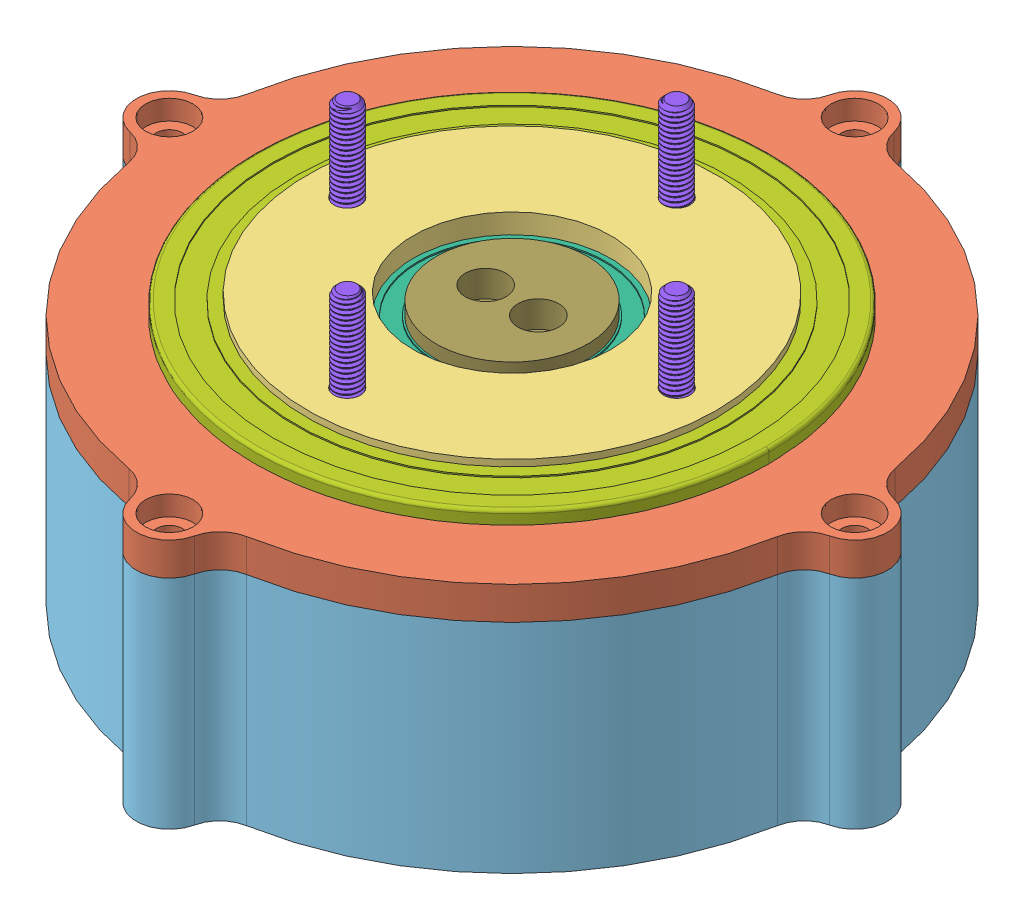
SolidWorks assembly Cycloidal Drive v1.2, configuration Default. Lengths in mm.
Overall size (114 54 114).
165 component instances, 18 part files, 39 mates.
Components (placement in the parent):
- Cycloid v1.4-2: Cycloid v1.4 [Default] at (0.2483 21.0104 2.4876) x (0.928028 0 -0.37251) z (0.37251 0 0.928028) size (80.42 7.02 80.39)
- Cycloid v1.4-1: Cycloid v1.4 [Default] at (-0.2483 13.0076 -2.4876) x (0.977963 0 0.208778) z (-0.208778 0 0.977963) size (80.42 7.02 80.39)
- Top v1.0-2: Top v1.0 [Default] at (0 33 0) x (1 0 0) z (0 1 0) size (114 114 9)
- TopCap v1.1-2: TopCap v1.1 [Default] at (0 38 0) x (1 0 0.000064) z (0 1 0) size (61.99 61.99 13)
- BottomCap v1.1-2: BottomCap v1.1 [Default] at (0 1 0) x (1 0 0) z (0 -1 0) size (63.99 63.99 12)
- Housing v1.3-1: Housing v1.3 [Default] at origin size (114 33 114)
- 6804-3: 6804 [Default] at (0 34.4948 0) x (0 1 0) z (0 0 -1) size (7.01 32.02 32)
- 6804-2: 6804 [Default] at (0.2483 24.5052 2.4876) x (0 1 0) z (0 0 -1) size (7.01 32.02 32)
- 6804-1: 6804 [Default] at (-0.2483 16.5024 -2.4876) x (0 1 0) z (1 0 0) size (7.01 32.02 32)
- 6812-1: 6812 [Default] at (0 6.0038 0) x (0 1 0) z (0 0 -1) size (10.01 78 78)
- 6812-2: 6812 [Default] at (0 35.0038 0) x (0 -1 0) z (0 0 1) size (10.01 78 78)
- MR84ZZ-5: MR84ZZ [Default] at (-25 13.0076 -0.0016) x (0 1 0) z (0.000038 0 -1) size (3 9.83 9.83) (hidden)
  - MR84ZZ_3-1: MR84ZZ_3 [Default] at origin size (0.15 7.4 7.4)
  - MR84ZZ_5-1: MR84ZZ_5 [Default] at (1.5 1.5 2.5981) x (1 0 0) z (0 -1 0) size (1.2 1.2 1.2) (hidden)
  - MR84ZZ_5-2: MR84ZZ_5 [Default] at (1.5 2.5981 1.5) x (1 0 0) z (0 -1 0) size (1.2 1.2 1.2) (hidden)
  - MR84ZZ_5-3: MR84ZZ_5 [Default] at (1.5 3 0) x (1 0 0) z (0 -1 0) size (1.2 1.2 1.2) (hidden)
  - MR84ZZ_5-4: MR84ZZ_5 [Default] at (1.5 2.5981 -1.5) x (1 0 0) z (0 -1 0) size (1.2 1.2 1.2) (hidden)
  - MR84ZZ_5-5: MR84ZZ_5 [Default] at (1.5 1.5 -2.5981) x (1 0 0) z (0 -1 0) size (1.2 1.2 1.2) (hidden)
  - MR84ZZ_5-6: MR84ZZ_5 [Default] at (1.5 0 -3) x (1 0 0) z (0 -1 0) size (1.2 1.2 1.2) (hidden)
  - MR84ZZ_5-7: MR84ZZ_5 [Default] at (1.5 -1.5 -2.5981) x (1 0 0) z (0 -1 0) size (1.2 1.2 1.2) (hidden)
  - MR84ZZ_5-8: MR84ZZ_5 [Default] at (1.5 -2.5981 -1.5) x (1 0 0) z (0 -1 0) size (1.2 1.2 1.2) (hidden)
  - MR84ZZ_5-9: MR84ZZ_5 [Default] at (1.5 -3 0) x (1 0 0) z (0 -1 0) size (1.2 1.2 1.2) (hidden)
  - MR84ZZ_5-10: MR84ZZ_5 [Default] at (1.5 -2.5981 1.5) x (1 0 0) z (0 -1 0) size (1.2 1.2 1.2) (hidden)
  - MR84ZZ_5-11: MR84ZZ_5 [Default] at (1.5 -1.5 2.5981) x (1 0 0) z (0 -1 0) size (1.2 1.2 1.2) (hidden)
  - MR84ZZ_5-12: MR84ZZ_5 [Default] at (1.5 0 3) x (1 0 0) z (0 -1 0) size (1.2 1.2 1.2) (hidden)
  - MR84ZZ_18-1: MR84ZZ_18 [Default] at (0.3984 0 0) x (-1 0 0) z (0 -1 0) size (0.15 7.4 7.4)
  - MR84ZZ_20-1: MR84ZZ_20 [Default] x (1 0 0) z (0 -1 0) size (3 5.29 5.29)
  - MR84ZZ_22-1: MR84ZZ_22 [Default] at origin size (3 9.83 9.83)
- MR84ZZ-1: MR84ZZ [Default] at (-25 21.0104 -0.0016) x (0 1 0) z (0.000038 0 -1) size (3 9.83 9.83) (hidden)
  - MR84ZZ_3-1: MR84ZZ_3 [Default] at origin size (0.15 7.4 7.4)
  - MR84ZZ_5-1: MR84ZZ_5 [Default] at (1.5 1.5 2.5981) x (1 0 0) z (0 -1 0) size (1.2 1.2 1.2) (hidden)
  - MR84ZZ_5-2: MR84ZZ_5 [Default] at (1.5 2.5981 1.5) x (1 0 0) z (0 -1 0) size (1.2 1.2 1.2) (hidden)
  - MR84ZZ_5-3: MR84ZZ_5 [Default] at (1.5 3 0) x (1 0 0) z (0 -1 0) size (1.2 1.2 1.2) (hidden)
  - MR84ZZ_5-4: MR84ZZ_5 [Default] at (1.5 2.5981 -1.5) x (1 0 0) z (0 -1 0) size (1.2 1.2 1.2) (hidden)
  - MR84ZZ_5-5: MR84ZZ_5 [Default] at (1.5 1.5 -2.5981) x (1 0 0) z (0 -1 0) size (1.2 1.2 1.2) (hidden)
  - MR84ZZ_5-6: MR84ZZ_5 [Default] at (1.5 0 -3) x (1 0 0) z (0 -1 0) size (1.2 1.2 1.2) (hidden)
  - MR84ZZ_5-7: MR84ZZ_5 [Default] at (1.5 -1.5 -2.5981) x (1 0 0) z (0 -1 0) size (1.2 1.2 1.2) (hidden)
  - MR84ZZ_5-8: MR84ZZ_5 [Default] at (1.5 -2.5981 -1.5) x (1 0 0) z (0 -1 0) size (1.2 1.2 1.2) (hidden)
  - MR84ZZ_5-9: MR84ZZ_5 [Default] at (1.5 -3 0) x (1 0 0) z (0 -1 0) size (1.2 1.2 1.2) (hidden)
  - MR84ZZ_5-10: MR84ZZ_5 [Default] at (1.5 -2.5981 1.5) x (1 0 0) z (0 -1 0) size (1.2 1.2 1.2) (hidden)
  - MR84ZZ_5-11: MR84ZZ_5 [Default] at (1.5 -1.5 2.5981) x (1 0 0) z (0 -1 0) size (1.2 1.2 1.2) (hidden)
  - MR84ZZ_5-12: MR84ZZ_5 [Default] at (1.5 0 3) x (1 0 0) z (0 -1 0) size (1.2 1.2 1.2) (hidden)
  - MR84ZZ_18-1: MR84ZZ_18 [Default] at (0.3984 0 0) x (-1 0 0) z (0 -1 0) size (0.15 7.4 7.4)
  - MR84ZZ_20-1: MR84ZZ_20 [Default] x (1 0 0) z (0 -1 0) size (3 5.29 5.29)
  - MR84ZZ_22-1: MR84ZZ_22 [Default] at origin size (3 9.83 9.83)
- M4_50-1: M4_50 [Default] at (-187.5016 -66 37.45) size (7.2 54 7.2)
- Dowel Pin-1: Dowel Pin [Default] at (-21.5 3 -37.2391) x (0.714611 0 -0.699522) z (0.699522 0 0.714611) size (6 30 6) (hidden)
- Dowel Pin-9: Dowel Pin [Default] at (7.4669 3 -42.3467) x (0.997068 0 -0.076522) z (0.076522 0 0.997068) size (6 30 6) (hidden)
- Dowel Pin-8: Dowel Pin [Default] at (32.9399 3 -27.6399) x (0.812986 0 0.582283) z (-0.582283 0 0.812986) size (6 30 6) (hidden)
- Dowel Pin-7: Dowel Pin [Default] at (43 3 0) x (0.248499 0 0.968632) z (-0.968632 0 0.248499) size (6 30 6) (hidden)
- Dowel Pin-6: Dowel Pin [Default] at (32.9399 3 27.6399) x (-0.432264 0 0.901747) z (-0.901747 0 -0.432264) size (6 30 6) (hidden)
- Dowel Pin-5: Dowel Pin [Default] at (7.4669 3 42.3467) x (-0.910765 0 0.412925) z (-0.412925 0 -0.910765) size (6 30 6) (hidden)
- Dowel Pin-4: Dowel Pin [Default] at (-21.5 3 37.2391) x (-0.963109 0 -0.26911) z (0.26911 0 -0.963109) size (6 30 6) (hidden)
- Dowel Pin-3: Dowel Pin [Default] at (-40.4068 3 14.7069) x (-0.564804 0 -0.825225) z (0.825225 0 -0.564804) size (6 30 6) (hidden)
- Dowel Pin-2: Dowel Pin [Default] at (-40.4068 3 -14.7069) x (0.097779 0 -0.995208) z (0.995208 0 0.097779) size (6 30 6) (hidden)
- M4_50-2: M4_50 [Default] at (-37.45 -66 -187.5016) x (0 0 1) z (-1 0 0) size (7.2 54 7.2)
- M4_50-3: M4_50 [Default] at (187.5016 -66 -37.45) x (-1 0 0) z (0 0 -1) size (7.2 54 7.2)
- M4_50-4: M4_50 [Default] at (37.45 -66 187.5016) x (0 0 -1) z (1 0 0) size (7.2 54 7.2)
- MR84ZZ-2: MR84ZZ [Default] at (0.0016 21.0104 -25) x (0 1 0) z (1 0 0.000038) size (3 9.83 9.83) (hidden)
  - MR84ZZ_3-1: MR84ZZ_3 [Default] at origin size (0.15 7.4 7.4)
  - MR84ZZ_5-1: MR84ZZ_5 [Default] at (1.5 1.5 2.5981) x (1 0 0) z (0 -1 0) size (1.2 1.2 1.2) (hidden)
  - MR84ZZ_5-2: MR84ZZ_5 [Default] at (1.5 2.5981 1.5) x (1 0 0) z (0 -1 0) size (1.2 1.2 1.2) (hidden)
  - MR84ZZ_5-3: MR84ZZ_5 [Default] at (1.5 3 0) x (1 0 0) z (0 -1 0) size (1.2 1.2 1.2) (hidden)
  - MR84ZZ_5-4: MR84ZZ_5 [Default] at (1.5 2.5981 -1.5) x (1 0 0) z (0 -1 0) size (1.2 1.2 1.2) (hidden)
  - MR84ZZ_5-5: MR84ZZ_5 [Default] at (1.5 1.5 -2.5981) x (1 0 0) z (0 -1 0) size (1.2 1.2 1.2) (hidden)
  - MR84ZZ_5-6: MR84ZZ_5 [Default] at (1.5 0 -3) x (1 0 0) z (0 -1 0) size (1.2 1.2 1.2) (hidden)
  - MR84ZZ_5-7: MR84ZZ_5 [Default] at (1.5 -1.5 -2.5981) x (1 0 0) z (0 -1 0) size (1.2 1.2 1.2) (hidden)
  - MR84ZZ_5-8: MR84ZZ_5 [Default] at (1.5 -2.5981 -1.5) x (1 0 0) z (0 -1 0) size (1.2 1.2 1.2) (hidden)
  - MR84ZZ_5-9: MR84ZZ_5 [Default] at (1.5 -3 0) x (1 0 0) z (0 -1 0) size (1.2 1.2 1.2) (hidden)
  - MR84ZZ_5-10: MR84ZZ_5 [Default] at (1.5 -2.5981 1.5) x (1 0 0) z (0 -1 0) size (1.2 1.2 1.2) (hidden)
  - MR84ZZ_5-11: MR84ZZ_5 [Default] at (1.5 -1.5 2.5981) x (1 0 0) z (0 -1 0) size (1.2 1.2 1.2) (hidden)
  - MR84ZZ_5-12: MR84ZZ_5 [Default] at (1.5 0 3) x (1 0 0) z (0 -1 0) size (1.2 1.2 1.2) (hidden)
  - MR84ZZ_18-1: MR84ZZ_18 [Default] at (0.3984 0 0) x (-1 0 0) z (0 -1 0) size (0.15 7.4 7.4)
  - MR84ZZ_20-1: MR84ZZ_20 [Default] x (1 0 0) z (0 -1 0) size (3 5.29 5.29)
  - MR84ZZ_22-1: MR84ZZ_22 [Default] at origin size (3 9.83 9.83)
- MR84ZZ-3: MR84ZZ [Default] at (25 21.0104 0.0016) x (0 1 0) z (-0.000038 0 1) size (3 9.83 9.83) (hidden)
  - MR84ZZ_3-1: MR84ZZ_3 [Default] at origin size (0.15 7.4 7.4)
  - MR84ZZ_5-1: MR84ZZ_5 [Default] at (1.5 1.5 2.5981) x (1 0 0) z (0 -1 0) size (1.2 1.2 1.2) (hidden)
  - MR84ZZ_5-2: MR84ZZ_5 [Default] at (1.5 2.5981 1.5) x (1 0 0) z (0 -1 0) size (1.2 1.2 1.2) (hidden)
  - MR84ZZ_5-3: MR84ZZ_5 [Default] at (1.5 3 0) x (1 0 0) z (0 -1 0) size (1.2 1.2 1.2) (hidden)
  - MR84ZZ_5-4: MR84ZZ_5 [Default] at (1.5 2.5981 -1.5) x (1 0 0) z (0 -1 0) size (1.2 1.2 1.2) (hidden)
  - MR84ZZ_5-5: MR84ZZ_5 [Default] at (1.5 1.5 -2.5981) x (1 0 0) z (0 -1 0) size (1.2 1.2 1.2) (hidden)
  - MR84ZZ_5-6: MR84ZZ_5 [Default] at (1.5 0 -3) x (1 0 0) z (0 -1 0) size (1.2 1.2 1.2) (hidden)
  - MR84ZZ_5-7: MR84ZZ_5 [Default] at (1.5 -1.5 -2.5981) x (1 0 0) z (0 -1 0) size (1.2 1.2 1.2) (hidden)
  - MR84ZZ_5-8: MR84ZZ_5 [Default] at (1.5 -2.5981 -1.5) x (1 0 0) z (0 -1 0) size (1.2 1.2 1.2) (hidden)
  - MR84ZZ_5-9: MR84ZZ_5 [Default] at (1.5 -3 0) x (1 0 0) z (0 -1 0) size (1.2 1.2 1.2) (hidden)
  - MR84ZZ_5-10: MR84ZZ_5 [Default] at (1.5 -2.5981 1.5) x (1 0 0) z (0 -1 0) size (1.2 1.2 1.2) (hidden)
  - MR84ZZ_5-11: MR84ZZ_5 [Default] at (1.5 -1.5 2.5981) x (1 0 0) z (0 -1 0) size (1.2 1.2 1.2) (hidden)
  - MR84ZZ_5-12: MR84ZZ_5 [Default] at (1.5 0 3) x (1 0 0) z (0 -1 0) size (1.2 1.2 1.2) (hidden)
  - MR84ZZ_18-1: MR84ZZ_18 [Default] at (0.3984 0 0) x (-1 0 0) z (0 -1 0) size (0.15 7.4 7.4)
  - MR84ZZ_20-1: MR84ZZ_20 [Default] x (1 0 0) z (0 -1 0) size (3 5.29 5.29)
  - MR84ZZ_22-1: MR84ZZ_22 [Default] at origin size (3 9.83 9.83)
- MR84ZZ-4: MR84ZZ [Default] at (-0.0016 21.0104 25) x (0 1 0) z (-1 0 -0.000038) size (3 9.83 9.83) (hidden)
  - MR84ZZ_3-1: MR84ZZ_3 [Default] at origin size (0.15 7.4 7.4)
  - MR84ZZ_5-1: MR84ZZ_5 [Default] at (1.5 1.5 2.5981) x (1 0 0) z (0 -1 0) size (1.2 1.2 1.2) (hidden)
  - MR84ZZ_5-2: MR84ZZ_5 [Default] at (1.5 2.5981 1.5) x (1 0 0) z (0 -1 0) size (1.2 1.2 1.2) (hidden)
  - MR84ZZ_5-3: MR84ZZ_5 [Default] at (1.5 3 0) x (1 0 0) z (0 -1 0) size (1.2 1.2 1.2) (hidden)
  - MR84ZZ_5-4: MR84ZZ_5 [Default] at (1.5 2.5981 -1.5) x (1 0 0) z (0 -1 0) size (1.2 1.2 1.2) (hidden)
  - MR84ZZ_5-5: MR84ZZ_5 [Default] at (1.5 1.5 -2.5981) x (1 0 0) z (0 -1 0) size (1.2 1.2 1.2) (hidden)
  - MR84ZZ_5-6: MR84ZZ_5 [Default] at (1.5 0 -3) x (1 0 0) z (0 -1 0) size (1.2 1.2 1.2) (hidden)
  - MR84ZZ_5-7: MR84ZZ_5 [Default] at (1.5 -1.5 -2.5981) x (1 0 0) z (0 -1 0) size (1.2 1.2 1.2) (hidden)
  - MR84ZZ_5-8: MR84ZZ_5 [Default] at (1.5 -2.5981 -1.5) x (1 0 0) z (0 -1 0) size (1.2 1.2 1.2) (hidden)
  - MR84ZZ_5-9: MR84ZZ_5 [Default] at (1.5 -3 0) x (1 0 0) z (0 -1 0) size (1.2 1.2 1.2) (hidden)
  - MR84ZZ_5-10: MR84ZZ_5 [Default] at (1.5 -2.5981 1.5) x (1 0 0) z (0 -1 0) size (1.2 1.2 1.2) (hidden)
  - MR84ZZ_5-11: MR84ZZ_5 [Default] at (1.5 -1.5 2.5981) x (1 0 0) z (0 -1 0) size (1.2 1.2 1.2) (hidden)
  - MR84ZZ_5-12: MR84ZZ_5 [Default] at (1.5 0 3) x (1 0 0) z (0 -1 0) size (1.2 1.2 1.2) (hidden)
  - MR84ZZ_18-1: MR84ZZ_18 [Default] at (0.3984 0 0) x (-1 0 0) z (0 -1 0) size (0.15 7.4 7.4)
  - MR84ZZ_20-1: MR84ZZ_20 [Default] x (1 0 0) z (0 -1 0) size (3 5.29 5.29)
  - MR84ZZ_22-1: MR84ZZ_22 [Default] at origin size (3 9.83 9.83)
- MR84ZZ-6: MR84ZZ [Default] at (0.0016 13.0076 -25) x (0 1 0) z (1 0 0.000038) size (3 9.83 9.83) (hidden)
  - MR84ZZ_3-1: MR84ZZ_3 [Default] at origin size (0.15 7.4 7.4)
  - MR84ZZ_5-1: MR84ZZ_5 [Default] at (1.5 1.5 2.5981) x (1 0 0) z (0 -1 0) size (1.2 1.2 1.2) (hidden)
  - MR84ZZ_5-2: MR84ZZ_5 [Default] at (1.5 2.5981 1.5) x (1 0 0) z (0 -1 0) size (1.2 1.2 1.2) (hidden)
  - MR84ZZ_5-3: MR84ZZ_5 [Default] at (1.5 3 0) x (1 0 0) z (0 -1 0) size (1.2 1.2 1.2) (hidden)
  - MR84ZZ_5-4: MR84ZZ_5 [Default] at (1.5 2.5981 -1.5) x (1 0 0) z (0 -1 0) size (1.2 1.2 1.2) (hidden)
  - MR84ZZ_5-5: MR84ZZ_5 [Default] at (1.5 1.5 -2.5981) x (1 0 0) z (0 -1 0) size (1.2 1.2 1.2) (hidden)
  - MR84ZZ_5-6: MR84ZZ_5 [Default] at (1.5 0 -3) x (1 0 0) z (0 -1 0) size (1.2 1.2 1.2) (hidden)
  - MR84ZZ_5-7: MR84ZZ_5 [Default] at (1.5 -1.5 -2.5981) x (1 0 0) z (0 -1 0) size (1.2 1.2 1.2) (hidden)
  - MR84ZZ_5-8: MR84ZZ_5 [Default] at (1.5 -2.5981 -1.5) x (1 0 0) z (0 -1 0) size (1.2 1.2 1.2) (hidden)
  - MR84ZZ_5-9: MR84ZZ_5 [Default] at (1.5 -3 0) x (1 0 0) z (0 -1 0) size (1.2 1.2 1.2) (hidden)
  - MR84ZZ_5-10: MR84ZZ_5 [Default] at (1.5 -2.5981 1.5) x (1 0 0) z (0 -1 0) size (1.2 1.2 1.2) (hidden)
  - MR84ZZ_5-11: MR84ZZ_5 [Default] at (1.5 -1.5 2.5981) x (1 0 0) z (0 -1 0) size (1.2 1.2 1.2) (hidden)
  - MR84ZZ_5-12: MR84ZZ_5 [Default] at (1.5 0 3) x (1 0 0) z (0 -1 0) size (1.2 1.2 1.2) (hidden)
  - MR84ZZ_18-1: MR84ZZ_18 [Default] at (0.3984 0 0) x (-1 0 0) z (0 -1 0) size (0.15 7.4 7.4)
  - MR84ZZ_20-1: MR84ZZ_20 [Default] x (1 0 0) z (0 -1 0) size (3 5.29 5.29)
  - MR84ZZ_22-1: MR84ZZ_22 [Default] at origin size (3 9.83 9.83)
- MR84ZZ-7: MR84ZZ [Default] at (25 13.0076 0.0016) x (0 1 0) z (-0.000038 0 1) size (3 9.83 9.83) (hidden)
  - MR84ZZ_3-1: MR84ZZ_3 [Default] at origin size (0.15 7.4 7.4)
  - MR84ZZ_5-1: MR84ZZ_5 [Default] at (1.5 1.5 2.5981) x (1 0 0) z (0 -1 0) size (1.2 1.2 1.2) (hidden)
  - MR84ZZ_5-2: MR84ZZ_5 [Default] at (1.5 2.5981 1.5) x (1 0 0) z (0 -1 0) size (1.2 1.2 1.2) (hidden)
  - MR84ZZ_5-3: MR84ZZ_5 [Default] at (1.5 3 0) x (1 0 0) z (0 -1 0) size (1.2 1.2 1.2) (hidden)
  - MR84ZZ_5-4: MR84ZZ_5 [Default] at (1.5 2.5981 -1.5) x (1 0 0) z (0 -1 0) size (1.2 1.2 1.2) (hidden)
  - MR84ZZ_5-5: MR84ZZ_5 [Default] at (1.5 1.5 -2.5981) x (1 0 0) z (0 -1 0) size (1.2 1.2 1.2) (hidden)
  - MR84ZZ_5-6: MR84ZZ_5 [Default] at (1.5 0 -3) x (1 0 0) z (0 -1 0) size (1.2 1.2 1.2) (hidden)
  - MR84ZZ_5-7: MR84ZZ_5 [Default] at (1.5 -1.5 -2.5981) x (1 0 0) z (0 -1 0) size (1.2 1.2 1.2) (hidden)
  - MR84ZZ_5-8: MR84ZZ_5 [Default] at (1.5 -2.5981 -1.5) x (1 0 0) z (0 -1 0) size (1.2 1.2 1.2) (hidden)
  - MR84ZZ_5-9: MR84ZZ_5 [Default] at (1.5 -3 0) x (1 0 0) z (0 -1 0) size (1.2 1.2 1.2) (hidden)
  - MR84ZZ_5-10: MR84ZZ_5 [Default] at (1.5 -2.5981 1.5) x (1 0 0) z (0 -1 0) size (1.2 1.2 1.2) (hidden)
  - MR84ZZ_5-11: MR84ZZ_5 [Default] at (1.5 -1.5 2.5981) x (1 0 0) z (0 -1 0) size (1.2 1.2 1.2) (hidden)
  - MR84ZZ_5-12: MR84ZZ_5 [Default] at (1.5 0 3) x (1 0 0) z (0 -1 0) size (1.2 1.2 1.2) (hidden)
  - MR84ZZ_18-1: MR84ZZ_18 [Default] at (0.3984 0 0) x (-1 0 0) z (0 -1 0) size (0.15 7.4 7.4)
  - MR84ZZ_20-1: MR84ZZ_20 [Default] x (1 0 0) z (0 -1 0) size (3 5.29 5.29)
  - MR84ZZ_22-1: MR84ZZ_22 [Default] at origin size (3 9.83 9.83)
- MR84ZZ-8: MR84ZZ [Default] at (-0.0016 13.0076 25) x (0 1 0) z (-1 0 -0.000038) size (3 9.83 9.83) (hidden)
  - MR84ZZ_3-1: MR84ZZ_3 [Default] at origin size (0.15 7.4 7.4)
  - MR84ZZ_5-1: MR84ZZ_5 [Default] at (1.5 1.5 2.5981) x (1 0 0) z (0 -1 0) size (1.2 1.2 1.2) (hidden)
  - MR84ZZ_5-2: MR84ZZ_5 [Default] at (1.5 2.5981 1.5) x (1 0 0) z (0 -1 0) size (1.2 1.2 1.2) (hidden)
  - MR84ZZ_5-3: MR84ZZ_5 [Default] at (1.5 3 0) x (1 0 0) z (0 -1 0) size (1.2 1.2 1.2) (hidden)
  - MR84ZZ_5-4: MR84ZZ_5 [Default] at (1.5 2.5981 -1.5) x (1 0 0) z (0 -1 0) size (1.2 1.2 1.2) (hidden)
  - MR84ZZ_5-5: MR84ZZ_5 [Default] at (1.5 1.5 -2.5981) x (1 0 0) z (0 -1 0) size (1.2 1.2 1.2) (hidden)
  - MR84ZZ_5-6: MR84ZZ_5 [Default] at (1.5 0 -3) x (1 0 0) z (0 -1 0) size (1.2 1.2 1.2) (hidden)
  - MR84ZZ_5-7: MR84ZZ_5 [Default] at (1.5 -1.5 -2.5981) x (1 0 0) z (0 -1 0) size (1.2 1.2 1.2) (hidden)
  - MR84ZZ_5-8: MR84ZZ_5 [Default] at (1.5 -2.5981 -1.5) x (1 0 0) z (0 -1 0) size (1.2 1.2 1.2) (hidden)
  - MR84ZZ_5-9: MR84ZZ_5 [Default] at (1.5 -3 0) x (1 0 0) z (0 -1 0) size (1.2 1.2 1.2) (hidden)
  - MR84ZZ_5-10: MR84ZZ_5 [Default] at (1.5 -2.5981 1.5) x (1 0 0) z (0 -1 0) size (1.2 1.2 1.2) (hidden)
  - MR84ZZ_5-11: MR84ZZ_5 [Default] at (1.5 -1.5 2.5981) x (1 0 0) z (0 -1 0) size (1.2 1.2 1.2) (hidden)
  - MR84ZZ_5-12: MR84ZZ_5 [Default] at (1.5 0 3) x (1 0 0) z (0 -1 0) size (1.2 1.2 1.2) (hidden)
  - MR84ZZ_18-1: MR84ZZ_18 [Default] at (0.3984 0 0) x (-1 0 0) z (0 -1 0) size (0.15 7.4 7.4)
  - MR84ZZ_20-1: MR84ZZ_20 [Default] x (1 0 0) z (0 -1 0) size (3 5.29 5.29)
  - MR84ZZ_22-1: MR84ZZ_22 [Default] at origin size (3 9.83 9.83)
- Eccentric Shaft Assembly-1: Eccentric Shaft Assembly [Default] at origin size (36 40 36)
  - Eccentric Shaft Bottom-1: Eccentric Shaft Bottom [Default] at origin size (36 21 36)
  - Eccentric Shaft Middle-1: Eccentric Shaft Middle [Default] at origin size (24.3 11 22)
  - Eccentric Shaft Top-1: Eccentric Shaft Top [Default] at origin size (23.5 10 22)
  - Eccentric Shaft Cap-1: Eccentric Shaft Cap [Default] at origin size (23 5 23)
Mates (geometry in assembly coordinates):
- Concentric3: concentric: cylinder of assembly; cylinder of assembly; cylinder of Cycloid v1.4-1 through (-0.2483 13.0076 -2.4876) axis (0 1 0) radius 16; cylinder of 6804-1 through (-0.2483 12.6467 -2.4876) axis (0 -1 0) radius 16.002
- Coincident2: coincident: plane of assembly; plane of assembly; plane of Cycloid v1.4-1 through (7.5808 20.0076 -39.1613) normal (0 1 0); plane of 6804-1 through (-0.2483 20.0076 -2.4876) normal (0 1 0)
- Concentric4: concentric: cylinder of ? through (0 -1 0) axis (0 1 0) radius 39; cylinder of 6812-1 through (0 0.4996 0) axis (0 -1 0) radius 39.0017
- Distance2: distance = 1 mm: plane of ? through (0 0 0) normal (0 -1 0); plane of 6812-1 through (0 1 0) normal (0 -1 0)
- Distance1: distance = 2 mm: plane of assembly; plane of assembly; plane of 6812-1 through (0 11.0076 0) normal (0 1 0); plane of Cycloid v1.4-1 through (7.5808 13.0076 -39.1613) normal (0 -1 0)
- Concentric5: concentric: cylinder of assembly; cylinder of assembly; cylinder of Cycloid v1.4-2 through (0.2483 21.0104 2.4876) axis (0 1 0) radius 16; cylinder of 6804-2 through (0.2483 20.6495 2.4876) axis (0 -1 0) radius 16.002
- Coincident6: coincident: plane of assembly; plane of assembly; plane of Cycloid v1.4-2 through (-13.7208 28.0104 -32.3134) normal (0 1 0); plane of 6804-2 through (0.2483 28.0104 2.4876) normal (0 1 0)
- Concentric6: concentric: cylinder of 6812-1 through (0 0.4996 0) axis (0 -1 0) radius 29.9974; cylinder of ? through (0 10 0) axis (0 -1 0) radius 18
- Coincident7: coincident: plane of ? through (0 0 0) normal (0 -1 0); plane of ? through (0 0 0) normal (0 -1 0)
- Concentric7: concentric: cylinder of 6804-1 through (-0.2483 12.6467 -2.4876) axis (0 -1 0) radius 9.9949; cylinder of ? through (-0.2483 20 -2.4876) axis (0 -1 0) radius 10
- Concentric10: concentric: circle of 6804-2; cylinder of ? through (0.2483 30 2.4876) axis (0 -1 0) radius 10
- Concentric11: concentric: cylinder of ? through (0 38 0) axis (0 -1 0) radius 10; cylinder of 6804-3 through (0 30.6391 0) axis (0 -1 0) radius 9.9949
- Coincident8: coincident: plane of ? through (0 38 0) normal (0 1 0); plane of 6804-3 through (0 38 0) normal (0 1 0)
- Concentric17: concentric: cylinder of assembly; cylinder of assembly; cylinder of 6812-2 through (0 40.508 0) axis (0 1 0) radius 29.9974; cylinder of TopCap v1.1-2 through (0 31 0) axis (0 1 0) radius 29.9974
- Concentric19: concentric: cylinder of assembly; cylinder of assembly; cylinder of M4_50-4 through (25 4.5 0.0016) axis (0 -1 0) radius 1.95; cylinder of TopCap v1.1-2 through (25 28 0.0016) axis (0 1 0) radius 2
- Concentric20: concentric: cylinder of assembly; cylinder of assembly; cylinder of M4_50-1 through (-0.0016 4.5 25) axis (0 -1 0) radius 1.95; cylinder of TopCap v1.1-2 through (-0.0016 28 25) axis (0 1 0) radius 2
- Concentric21: concentric: cylinder of assembly; cylinder of assembly; cylinder of M4_50-2 through (-25 4.5 -0.0016) axis (0 -1 0) radius 1.95; cylinder of TopCap v1.1-2 through (-25 28 -0.0016) axis (0 1 0) radius 2
- Concentric22: concentric: cylinder of assembly; cylinder of assembly; cylinder of M4_50-3 through (0.0016 4.5 -25) axis (0 -1 0) radius 1.95; cylinder of TopCap v1.1-2 through (0.0016 28 -25) axis (0 1 0) radius 2
- Concentric23: concentric: cylinder of assembly; cylinder of assembly; cylinder of 6812-1 through (0 0.4996 0) axis (0 -1 0) radius 29.9974; cylinder of BottomCap v1.1-2 through (0 11 0) axis (0 -1 0) radius 29.9974
- Distance3: distance = 0 mm: plane of assembly; plane of assembly; plane of 6812-1 through (0 1 0) normal (0 -1 0); plane of BottomCap v1.1-2 through (0 1 0) normal (0 -1 0)
- Coincident25: coincident: plane of ? through (0.2483 21 2.4876) normal (0 1 0); plane of 6804-2 through (0.2483 21 2.4876) normal (0 -1 0)
- Concentric26: concentric: cylinder of assembly; cylinder of assembly; cylinder of M4_50-2 through (-25 4.5 -0.0016) axis (0 -1 0) radius 1.95; cylinder of MR84ZZ-1/MR84ZZ_20-1 through (-25 24.0104 -0.0016) axis (0 1 0) radius 2
- Concentric27: concentric: cylinder of assembly; cylinder of assembly; cylinder of M4_50-1 through (-0.0016 4.5 25) axis (0 -1 0) radius 1.95; cylinder of MR84ZZ-4/MR84ZZ_20-1 through (-0.0016 24.0104 25) axis (0 1 0) radius 2
- Concentric28: concentric: cylinder of assembly; cylinder of assembly; cylinder of M4_50-3 through (0.0016 4.5 -25) axis (0 -1 0) radius 1.95; cylinder of MR84ZZ-2/MR84ZZ_20-1 through (0.0016 24.0104 -25) axis (0 1 0) radius 2
- Concentric29: concentric: cylinder of assembly; cylinder of assembly; cylinder of M4_50-4 through (25 4.5 0.0016) axis (0 -1 0) radius 1.95; cylinder of MR84ZZ-3/MR84ZZ_20-1 through (25 24.0104 0.0016) axis (0 1 0) radius 2
- Concentric30: concentric: cylinder of assembly; cylinder of assembly; cylinder of MR84ZZ-5/MR84ZZ_20-1 through (-25 16.0076 -0.0016) axis (0 1 0) radius 2; cylinder of M4_50-2 through (-25 4.5 -0.0016) axis (0 -1 0) radius 1.95
- Coincident28: coincident: plane of Cycloid v1.4-1 through (7.5808 13.0076 -39.1613) normal (0 -1 0); plane of ? through (-21.1 13.0076 -0.0015) normal (0 -1 0)
- Coincident29: coincident: plane of Cycloid v1.4-2 through (-13.7208 21.0104 -32.3134) normal (0 -1 0); plane of ? through (-21.1 21.0104 -0.0015) normal (0 -1 0)
- Concentric31: concentric: cylinder of assembly; cylinder of assembly; cylinder of M4_50-1 through (-0.0016 4.5 25) axis (0 -1 0) radius 1.95; cylinder of MR84ZZ-8/MR84ZZ_20-1 through (-0.0016 16.0076 25) axis (0 1 0) radius 2
- Concentric33: concentric: cylinder of assembly; cylinder of assembly; cylinder of M4_50-4 through (25 4.5 0.0016) axis (0 -1 0) radius 1.95; cylinder of MR84ZZ-7/MR84ZZ_20-1 through (25 16.0076 0.0016) axis (0 1 0) radius 2
- Concentric34: concentric: cylinder of assembly; cylinder of assembly; cylinder of M4_50-3 through (0.0016 4.5 -25) axis (0 -1 0) radius 1.95; cylinder of MR84ZZ-6/MR84ZZ_20-1 through (0.0016 16.0076 -25) axis (0 1 0) radius 2
- Coincident32: coincident: plane of assembly; plane of assembly; plane of 6804-3 through (0 38 0) normal (0 1 0); plane of TopCap v1.1-2 through (0 38 0) normal (0 -1 0)
- Concentric35: concentric: cylinder of ? through (-11.4431 5.5 1.1423) axis (0 1 0) radius 1.75; cylinder of ? through (-11.4431 21.7632 1.1423) axis (0 1 0) radius 3.6
- Concentric36: concentric: cylinder of BottomCap v1.1-2 through (0 11 0) axis (0 -1 0) radius 20; cylinder of ? through (0 10 0) axis (0 -1 0) radius 18
- Coincident34: coincident: plane of 6804-3 through (0 38 0) normal (0 1 0); plane of ? through (0 38 0) normal (0 1 0)
- Concentric38: concentric: cylinder of ? through (52 -14.1421 0) axis (0 1 0) radius 2; cylinder of Top v1.0-2 through (52 35 0) axis (0 1 0) radius 3.6
- Concentric39: concentric: cylinder of Top v1.0-2 through (0 38 0) axis (0 -1 0) radius 50; cylinder of ? through (0 5 0) axis (0 -1 0) radius 50
- Coincident36: coincident: plane of assembly; plane of assembly; plane of Top v1.0-2 through (0 30 0) normal (0 1 0); plane of 6812-2 through (0 30 0) normal (0 -1 0)
- Coincident37: coincident: plane of Top v1.0-2 through (0 33 0) normal (0 -1 0); plane of ? through (0 33 0) normal (0 1 0)
